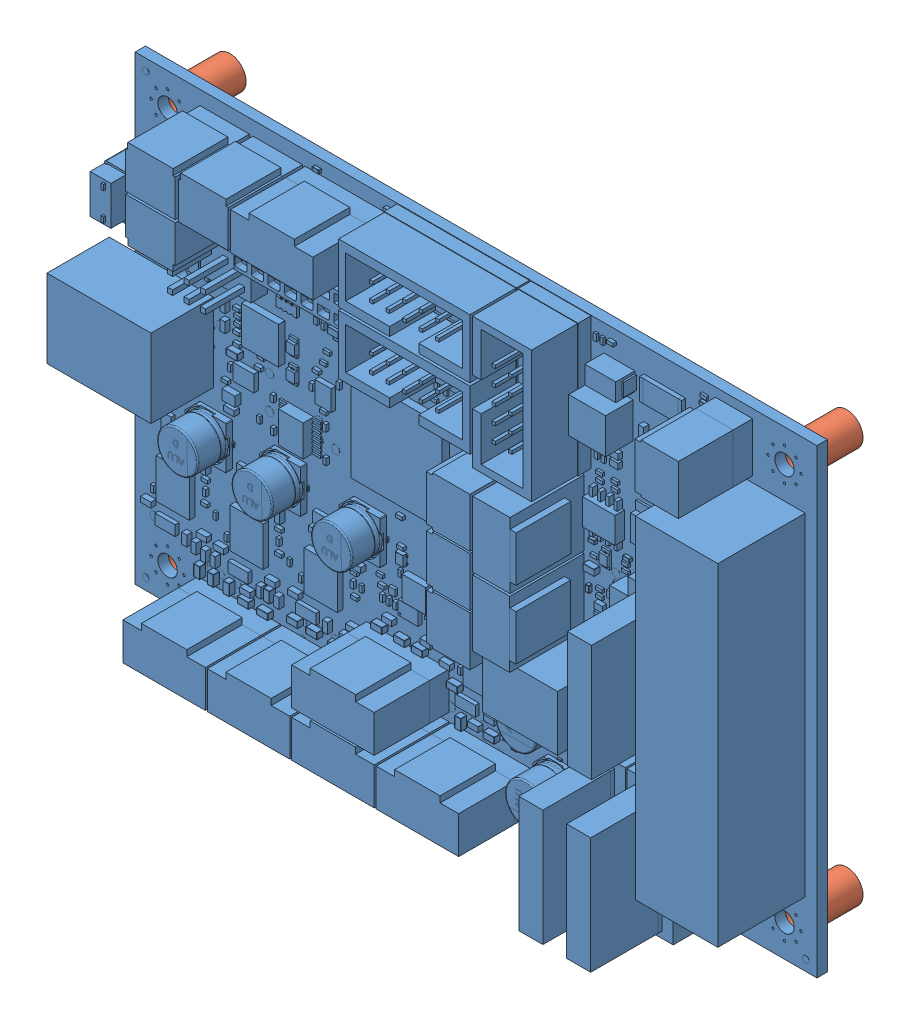
SolidWorks assembly EinsyAssembly_StandOff, configuration Default. Lengths in mm.
Overall size (108.28 71 27.59).
5 component instances, 2 part files, 8 mates.
Components (placement in the parent):
- Einsy_Rambo-1: Einsy_Rambo [Default] at (14.9676 86.704 68.4713) size (108.28 71 21.5)
- standOffs-1: standOffs [Default] at (92.9775 34.4902 66.8766) x (1 0 0) z (0 -1 0) size (5 8 5)
- standOffs-3: standOffs [Default] at (92.6031 96.0937 66.8766) x (0 1 0) z (1 0 0) size (5 8 5)
- standOffs-4: standOffs [Default] at (-2.0225 34.4902 66.8766) x (1 0 0) z (0 -1 0) size (5 8 5)
- standOffs-5: standOffs [Default] at (-2.0225 95.4902 66.8766) x (1 0 0) z (0 -1 0) size (5 8 5)
Mates (geometry in assembly coordinates):
- Concentric1: concentric anti-aligned: circle of Einsy_Rambo-1; circle of standOffs-1
- Coincident2: coincident anti-aligned: plane of Einsy_Rambo-1 through (-7.5114 29.605 66.8766) normal (0 0 -1); plane of standOffs-1 through (92.4886 34.6047 66.8766) normal (0 0 1)
- Coincident3: coincident anti-aligned: plane of Einsy_Rambo-1 through (-7.5114 29.605 66.8766) normal (0 0 -1); plane of standOffs-3 through (92.4886 95.6048 66.8766) normal (0 0 1)
- Coincident4: coincident anti-aligned: circle of Einsy_Rambo-1; circle of standOffs-3
- Coincident5: coincident anti-aligned: plane of Einsy_Rambo-1 through (-7.5114 29.605 66.8766) normal (0 0 -1); plane of standOffs-5 through (-2.5114 95.6048 66.8766) normal (0 0 1)
- Coincident6: coincident anti-aligned: circle of Einsy_Rambo-1; circle of standOffs-5
- Coincident7: coincident anti-aligned: plane of Einsy_Rambo-1 through (-7.5114 29.605 66.8766) normal (0 0 -1); plane of standOffs-4 through (-2.5114 34.6047 66.8766) normal (0 0 1)
- Coincident8: coincident anti-aligned: circle of Einsy_Rambo-1; circle of standOffs-4
